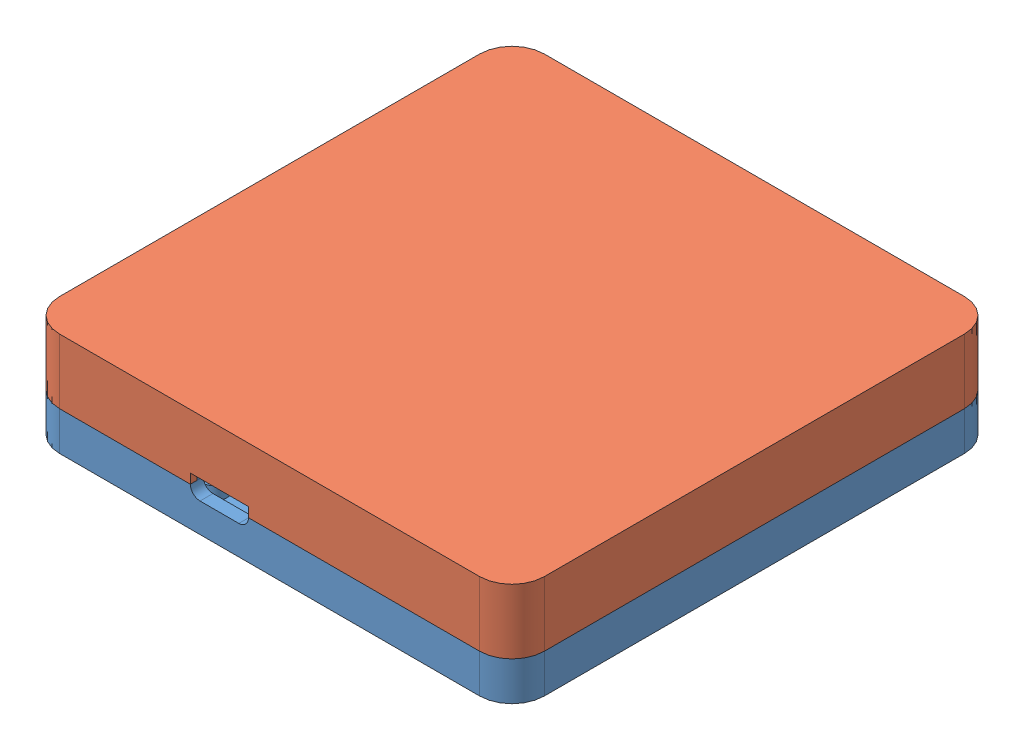
SolidWorks assembly Obudowa zestaw czujników BME280, configuration Domyślna. Lengths in mm.
Overall size (75 16 75).
2 component instances, 2 part files, 3 mates.
Components (placement in the parent):
- Obudowa góra BME280-1: Obudowa góra BME280 [Domyślna] at (-76.5624 -12.5092 150) size (75 10 75)
- Obudowa dół BME280-1: Obudowa dół BME280 [Domyślna] at (-76.5624 23.4908 150) size (75 10.7 75)
Mates (geometry in assembly coordinates):
- Koncentryczne1: concentric anti-aligned: cylinder of Obudowa1.11-1 through (-9.5624 -2.5092 133) axis (0 -1 0) radius 1.6; cylinder of Obudowa dół BME280-1 through (-9.5624 -7.0092 133) axis (0 1 0) radius 1.7
- Koncentryczne2: concentric anti-aligned: cylinder of Obudowa1.11-1 through (-9.5624 -2.5092 142) axis (0 -1 0) radius 1.6; cylinder of Obudowa dół BME280-1 through (-9.5624 -7.0092 142) axis (0 1 0) radius 1.7
- Wspólnie2: coincident anti-aligned: plane of Obudowa1.11-1 through (-6.5624 -6.5092 80) normal (0 1 0); plane of Obudowa dół BME280-1 through (-76.5624 -6.5092 150) normal (0 -1 0)
